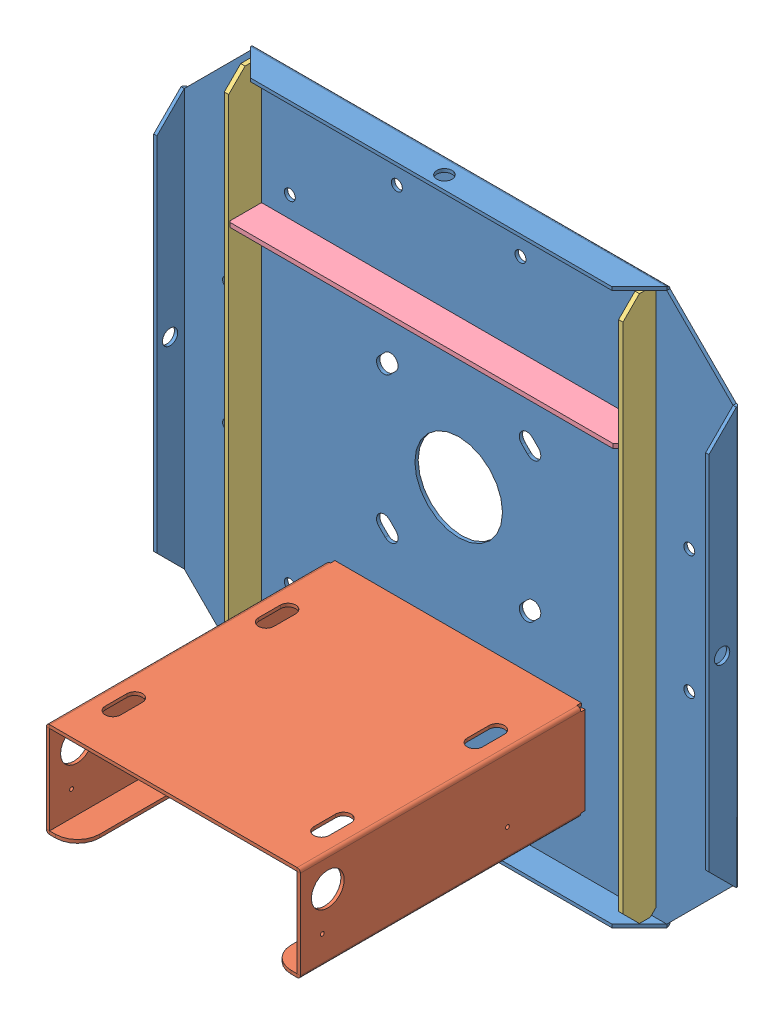
SolidWorks assembly 馬達座, configuration 預設. Lengths in mm.
Overall size (507.02 507.02 265).
5 component instances, 4 part files, 12 mates.
Components (placement in the parent):
- LB-A54-08-5-1: LB-A54-08-5 [預設] at (-3823.6914 -1684.3955 -13.9922) size (507.02 507.02 28)
- LB-A54-08-6-1: LB-A54-08-6 [預設] at (-5385.9746 -103.2703 -1252.2263) x (1 0 0) z (0 -1 0) size (232 265 86.99)
- LB-A54-08-7-1: LB-A54-08-7 [預設] at (-197.0794 -6179.9416 -1343.3795) x (0 1 0) z (1 0 0) size (498 30 4)
- LB-A54-08-7-2: LB-A54-08-7 [預設] at (162.9206 -6179.9416 -1343.3795) x (0 1 0) z (1 0 0) size (498 30 4)
- LB-A54-08-8-1: LB-A54-08-8 [預設] at (-7248.5612 142.2297 1336.6699) x (1 0 0) z (0 1 0) size (360 30 4)
Mates (geometry in assembly coordinates):
- 重合/共線/共點1: coincident: plane of LB-A54-08-5-1 through (427.4206 11.2297 -10.9922) normal (0 0 1); plane of LB-A54-08-6-1 through (56.4206 -106.2703 -10.9922) normal (0 0 -1)
- 重合/共線/共點2: coincident: line of LB-A54-08-5-1 through (102.4206 -103.2703 -13.9922) axis (0 -1 0); plane of LB-A54-08-6-1 through (102.4206 -192.7623 229.0078) normal (1 0 0)
- 重合/共線/共點3: coincident: line of LB-A54-08-5-1 through (-128.5794 -103.2703 -13.9922) axis (1 0 0); plane of LB-A54-08-6-1 through (185.9206 -103.2703 229.0078) normal (0 1 0)
- 重合/共線/共點4: coincident: plane of LB-A54-08-5-1 through (427.4206 11.2297 -10.9922) normal (0 0 1); plane of LB-A54-08-7-1 through (-193.0794 -231.2703 -10.9922) normal (0 0 -1)
- 重合/共線/共點5: coincident: line of LB-A54-08-5-1 through (-193.0794 261.7297 -13.9922) axis (0 -1 0); plane of LB-A54-08-7-1 through (-193.0794 -241.2703 -0.9922) normal (1 0 0)
- 重合/共線/共點6: coincident: point of LB-A54-08-5-1; plane of LB-A54-08-7-1 through (-193.0794 261.7297 -5.9922) normal (0 1 0)
- 重合/共線/共點7: coincident anti-aligned: plane of LB-A54-08-5-1 through (427.4206 11.2297 -10.9922) normal (0 0 1); plane of LB-A54-08-7-2 through (166.9206 -231.2703 -10.9922) normal (0 0 -1)
- 重合/共線/共點8: coincident: line of LB-A54-08-5-1 through (166.9206 261.7297 -13.9922) axis (0 -1 0); plane of LB-A54-08-7-2 through (166.9206 -241.2703 -0.9922) normal (1 0 0)
- 重合/共線/共點9: coincident: point of LB-A54-08-5-1; plane of LB-A54-08-7-2 through (166.9206 261.7297 -5.9922) normal (0 1 0)
- 重合/共線/共點10: coincident anti-aligned: plane of LB-A54-08-5-1 through (427.4206 11.2297 -10.9922) normal (0 0 1); plane of LB-A54-08-8-1 through (162.9206 146.2297 -10.9922) normal (0 0 -1)
- 重合/共線/共點11: coincident: line of LB-A54-08-5-1 through (-193.0794 146.2297 -13.9922) axis (1 0 0); plane of LB-A54-08-8-1 through (-197.0794 146.2297 -10.9922) normal (0 1 0)
- 重合/共線/共點12: coincident anti-aligned: plane of LB-A54-08-7-2 through (162.9206 -241.2703 -0.9922) normal (-1 0 0); plane of LB-A54-08-8-1 through (162.9206 146.2297 14.0078) normal (1 0 0)
